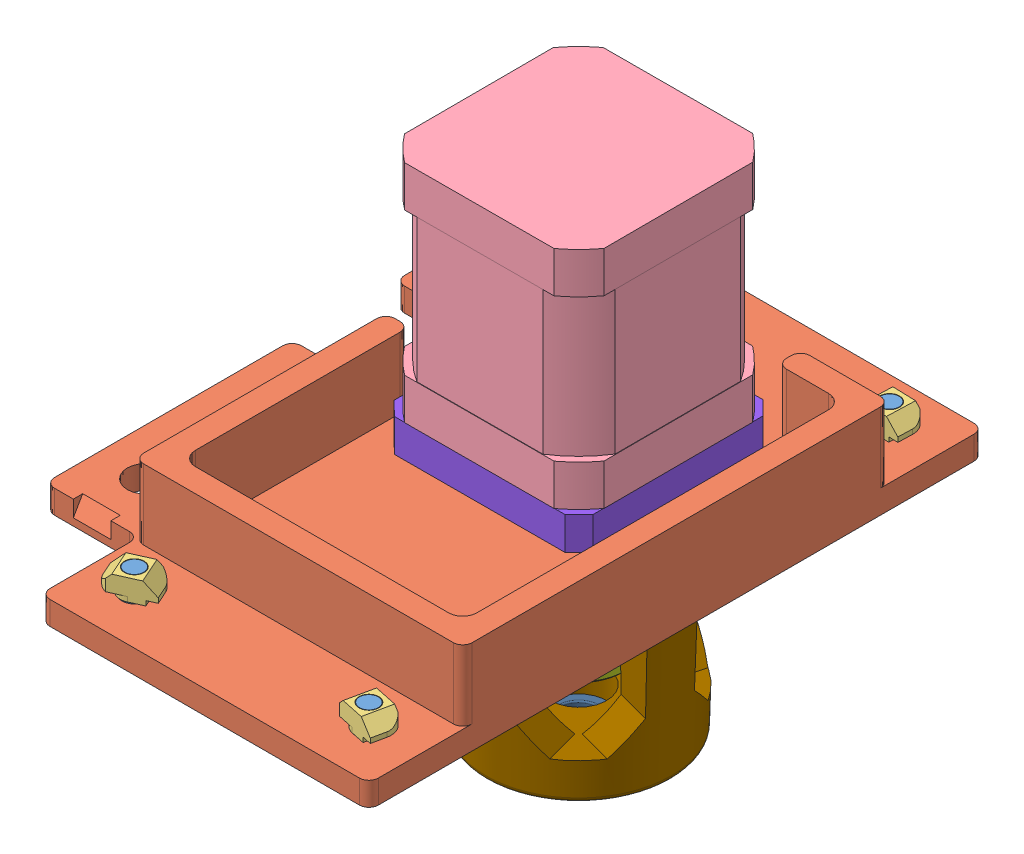
SolidWorks assembly front_right_z_plate_assembly, configuration Default. Lengths in mm.
Overall size (90 112 131).
27 component instances, 12 part files, 3 mates.
Components (placement in the parent):
- m5_low_profile_screw_template_M5 x 10-1: m5_low_profile_screw_template_M5 x 10 [Default] at (204.071 33.773 493.3157) x (0 1 0) z (0.787405 0 0.616437) size (11.62 9 9)
- m5_low_profile_screw_template_M5 x 10-2: m5_low_profile_screw_template_M5 x 10 [Default] at (254.071 33.773 493.3157) x (0 1 0) z (-0.857842 0 -0.513914) size (11.62 9 9)
- m5_low_profile_screw_template_M5 x 10-3: m5_low_profile_screw_template_M5 x 10 [Default] at (184.071 33.773 382.3157) x (0 1 0) z (0.29878 0 -0.954322) size (11.62 9 9)
- m5_low_profile_screw_template_M5 x 10-4: m5_low_profile_screw_template_M5 x 10 [Default] at (254.071 33.773 382.3157) x (0 1 0) z (-0.870585 0 -0.492019) size (11.62 9 9)
- front_z_panel_v2_Front Right Z Motor Plate-1: front_z_panel_v2_Front Right Z Motor Plate [Default] at (354.071 28.773 503.3157) x (-1 0 0) z (0 0 1) size (90 20 131)
- m5_locking_t_nut_20x20_generic-1: m5_locking_t_nut_20x20_generic [Default] at (253.4473 33.773 496.2502) x (0.978151 0 0.207896) z (0.207896 0 -0.978151) size (10 4.5 6)
- m5_locking_t_nut_20x20_generic-2: m5_locking_t_nut_20x20_generic [Default] at (205.2987 33.773 496.053) x (0.91243 0 -0.409233) z (-0.409233 0 -0.91243) size (10 4.5 6)
- m5_locking_t_nut_20x20_generic-3: m5_locking_t_nut_20x20_generic [Default] at (183.7809 33.773 385.3017) x (0.995316 0 0.096671) z (0.096671 0 -0.995316) size (10 4.5 6)
- m5_locking_t_nut_20x20_generic-4: m5_locking_t_nut_20x20_generic [Default] at (253.9739 33.773 385.3142) x (0.999476 0 0.03236) z (0.03236 0 -0.999476) size (10 4.5 6)
- Copy of z_motor_thrust_assy_printed^front_right_z_plate_assembly-1: Copy of z_motor_thrust_assy_printed^front_right_z_plate_assembly [Default] at (343.097 52.7839 401.3583) x (-0.999997 0 0.002418) z (0.002418 0 0.999997) size (42.42 112 42.42) (virtual)
  - z_motor_thrust_coupling_assembly_3-1: z_motor_thrust_coupling_assembly_3 [Default] at (547.6945 -11.7621 -290.9574) x (0 0 1) z (-1 0 0) size (42.42 92 42.42)
    - 17HM19-2004S-1: 17HM19-2004S [Default] at (307.9646 28.773 428.6645) x (0 0 -1) z (0 1 0) size (42.42 42.42 72)
    - couplings_cajc20-rd-5-8-1: couplings_cajc20-rd-5-8 [Default] at (307.9646 57.773 428.6645) x (0 1 0) z (0 0 1) size (30 20 20)
      - couplings_cajc20-rd-5-8_01-1: couplings_cajc20-rd-5-8_01 [Default] at origin size (8 18.12 18.12)
      - couplings_cajc20-rd-5-8_02-1: couplings_cajc20-rd-5-8_02 [Default] at origin size (19 20 19.99)
      - couplings_cajc20-rd-5-8_03-1: couplings_cajc20-rd-5-8_03 [Default] at origin size (19 19.99 20)
  - NEMA17_spacer_plate_7mm-1: NEMA17_spacer_plate_7mm [Default] at (119.03 24.0109 17.0072) x (-1 0 0) z (0 -1 0) size (42.3 42.3 7)
  - thrust_cage-1: thrust_cage [Default] at (119.03 44.6637 17.0072) x (0.002418 0 0.999997) z (-0.999997 0 0.002418) size (42.3 47 42.3)
  - AST_Bearings_F8-19M-1: AST_Bearings_F8-19M [Default] at (119.03 77.5109 17.0072) x (0.99905 0 -0.043582) z (0.043582 0 0.99905) size (19 7 19)
  - m3_stainless_steel_washer_90965A130-1: m3_stainless_steel_washer_90965A130 [90965A130] at (134.5301 32.0109 1.5071) x (1 0 0) z (0 1 0) size (7 7 0.6)
  - m3_stainless_steel_washer_90965A130-2: m3_stainless_steel_washer_90965A130 [90965A130] at (134.605 32.0109 32.5071) x (1 0 -0.000026) z (0 1 0) size (7 7 0.6)
  - m3_stainless_steel_washer_90965A130-3: m3_stainless_steel_washer_90965A130 [90965A130] at (103.5301 32.0109 1.5821) x (1 0 0) z (0 1 0) size (7 7 0.6)
  - m3_stainless_steel_washer_90965A130-4: m3_stainless_steel_washer_90965A130 [90965A130] at (103.6051 32.0109 32.582) x (1 0 0) z (0 1 0) size (7 7 0.6)
  - m3_20mm_buttohead_screw_92095A185-1: m3_20mm_buttohead_screw_92095A185 [92095A185] at (103.5301 34.2609 1.5821) x (1 0 0) z (0 1 0) size (5.7 5.7 21.83)
  - m3_20mm_buttohead_screw_92095A185-2: m3_20mm_buttohead_screw_92095A185 [92095A185] at (103.6051 34.2609 32.582) x (1 0 0) z (0 1 0) size (5.7 5.7 21.83)
  - m3_20mm_buttohead_screw_92095A185-3: m3_20mm_buttohead_screw_92095A185 [92095A185] at (134.5301 34.2609 1.5071) x (1 0 0) z (0 1 0) size (5.7 5.7 21.83)
  - m3_20mm_buttohead_screw_92095A185-4: m3_20mm_buttohead_screw_92095A185 [92095A185] at (134.605 34.2609 32.5071) x (1 0 0) z (0 1 0) size (5.7 5.7 21.83)
Mates (geometry in assembly coordinates):
- Coincident1: coincident anti-aligned: plane of front_z_panel_v2_Front Right Z Motor Plate-1 through (174.071 28.773 503.3157) normal (0 1 0); plane of Copy of z_motor_thrust_assy_printed^front_right_z_plate_assembly-1/NEMA17_spacer_plate_7mm-1 through (224.1084 28.773 418.6533) normal (0 -1 0)
- Concentric2: concentric aligned: cylinder of front_z_panel_v2_Front Right Z Motor Plate-1 through (208.571 28.774 434.1907) axis (0 -1 0) radius 1.7; circle of Copy of z_motor_thrust_assy_printed^front_right_z_plate_assembly-1/m3_20mm_buttohead_screw_92095A185-4
- Concentric3: concentric aligned: cylinder of front_z_panel_v2_Front Right Z Motor Plate-1 through (208.571 28.774 403.1907) axis (0 -1 0) radius 1.7; circle of Copy of z_motor_thrust_assy_printed^front_right_z_plate_assembly-1/m3_20mm_buttohead_screw_92095A185-3
